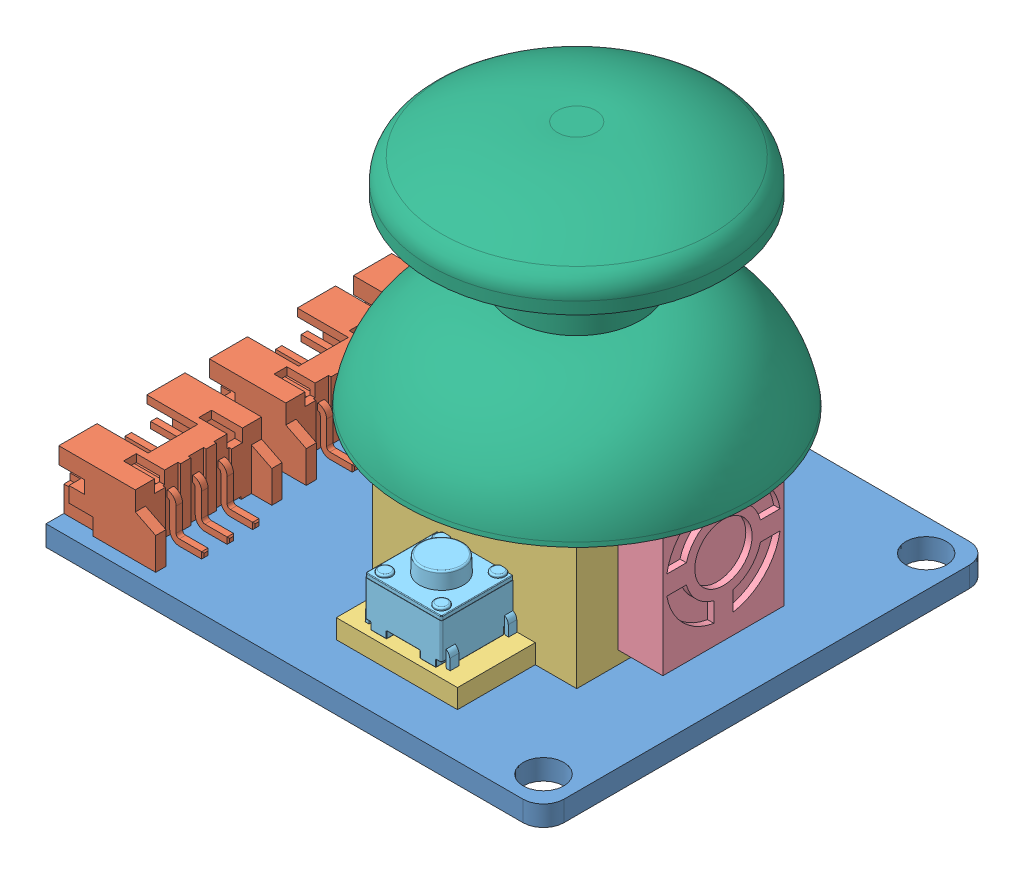
SolidWorks assembly DFRobot Joy V2, configuration По умолчанию. Lengths in mm.
Overall size (39.06 34.52 35).
10 component instances, 6 part files, 11 mates.
Components (placement in the parent):
- JoyPCB-1: JoyPCB [По умолчанию] at (-35.9085 10.3521 24.7582) size (39 1.6 35)
- S3B-PH-SM4-TB.stp-1: S3B-PH-SM4-TB.stp [По умолчанию] at (-55.4085 11.9521 13.2082) x (0 0 1) z (-1 0 0) size (9.9 4.8 8.6)
- S3B-PH-SM4-TB.stp-2: S3B-PH-SM4-TB.stp [По умолчанию] at (-55.4085 11.9521 24.5082) x (0 0 1) z (-1 0 0) size (9.9 4.8 8.6)
- S3B-PH-SM4-TB.stp-3: S3B-PH-SM4-TB.stp [По умолчанию] at (-55.4085 11.9521 36.3082) x (0 0 1) z (-1 0 0) size (9.9 4.8 8.6)
- Thumb Joystick-1: Thumb Joystick [기본] at (-30.5048 47.4521 27.6054) x (0 0 1) z (0 -1 0) size (30.12 30.12 34.52)
  - body-1: body [기본] at (-10.9543 -7.0963 23.5) size (22.1 16 23.5)
  - potentiometer-1: potentiometer [기본] at (-2.9543 -7.0963 29) x (-1 0 0) z (0 -1 0) size (9.5 14.5 3.5)
  - potentiometer-2: potentiometer [기본] at (-10.9543 0.9037 29.5) x (0 1 0) z (-1 0 0) size (9.5 14.5 3.5)
  - tactileswitch-short-1: tactileswitch-short [Default] at (7.6493 0.9037 34) x (0 -1 0) z (1 0 0) size (6.89 8.33 6.01)
  - joystickhead-1: joystickhead [기본] at (-21.7711 -52.5336 38.75) x (0.118335 0.992974 0) z (0 0 -1) size (27.11 27.11 19.35)
Mates (geometry in assembly coordinates):
- Distance2: distance = 1 mm: plane of JoyPCB-1 through (-55.4085 11.9521 7.2582) normal (0 0 -1); plane of S3B-PH-SM4-TB.stp-1 through (-52.4085 14.3521 8.2582) normal (0 0 -1)
- Coincident5: coincident: plane of JoyPCB-1 through (-35.9085 11.9521 24.7582) normal (0 1 0); plane of S3B-PH-SM4-TB.stp-1 through (-55.4085 11.9521 13.2082) normal (0 -1 0)
- Coincident6: coincident: plane of JoyPCB-1 through (-55.4085 11.9521 42.2582) normal (-1 0 0); plane of S3B-PH-SM4-TB.stp-3 through (-55.4085 16.7521 36.3082) normal (-1 0 0)
- Distance3: distance = 1 mm: plane of JoyPCB-1 through (-55.4085 11.9521 42.2582) normal (0 0 1); plane of S3B-PH-SM4-TB.stp-3 through (-52.4085 14.3521 41.2582) normal (0 0 1)
- Coincident8: coincident: plane of JoyPCB-1 through (-35.9085 11.9521 24.7582) normal (0 1 0); plane of S3B-PH-SM4-TB.stp-3 through (-55.4085 11.9521 36.3082) normal (0 -1 0)
- Coincident10: coincident: plane of JoyPCB-1 through (-55.4085 11.9521 42.2582) normal (-1 0 0); plane of S3B-PH-SM4-TB.stp-2 through (-55.4085 16.7521 24.5082) normal (-1 0 0)
- Coincident11: coincident: plane of JoyPCB-1 through (-35.9085 11.9521 24.7582) normal (0 1 0); plane of S3B-PH-SM4-TB.stp-2 through (-55.4085 11.9521 24.5082) normal (0 -1 0)
- Distance4: distance = 17 mm: plane of S3B-PH-SM4-TB.stp-2 through (-55.4085 14.8021 24.2582) normal (0 0 -1); plane of JoyPCB-1 through (-55.4085 11.9521 7.2582) normal (0 0 -1)
- Coincident13: coincident: plane of JoyPCB-1 through (-35.9085 11.9521 24.7582) normal (0 1 0); plane of Thumb Joystick-1/body-1 through (-23.4085 11.9521 16.6511) normal (0 -1 0)
- Distance5: distance = 4 mm: plane of Thumb Joystick-1/tactileswitch-short-1 through (-34.4121 16.8303 38.2582) normal (0 0 1); plane of JoyPCB-1 through (-55.4085 11.9521 42.2582) normal (0 0 1)
- Distance6: distance = 3.5 mm: plane of Thumb Joystick-1/potentiometer-1 through (-19.9085 18.4521 24.6511) normal (1 0 0); plane of JoyPCB-1 through (-16.4085 11.9521 42.2582) normal (1 0 0)
